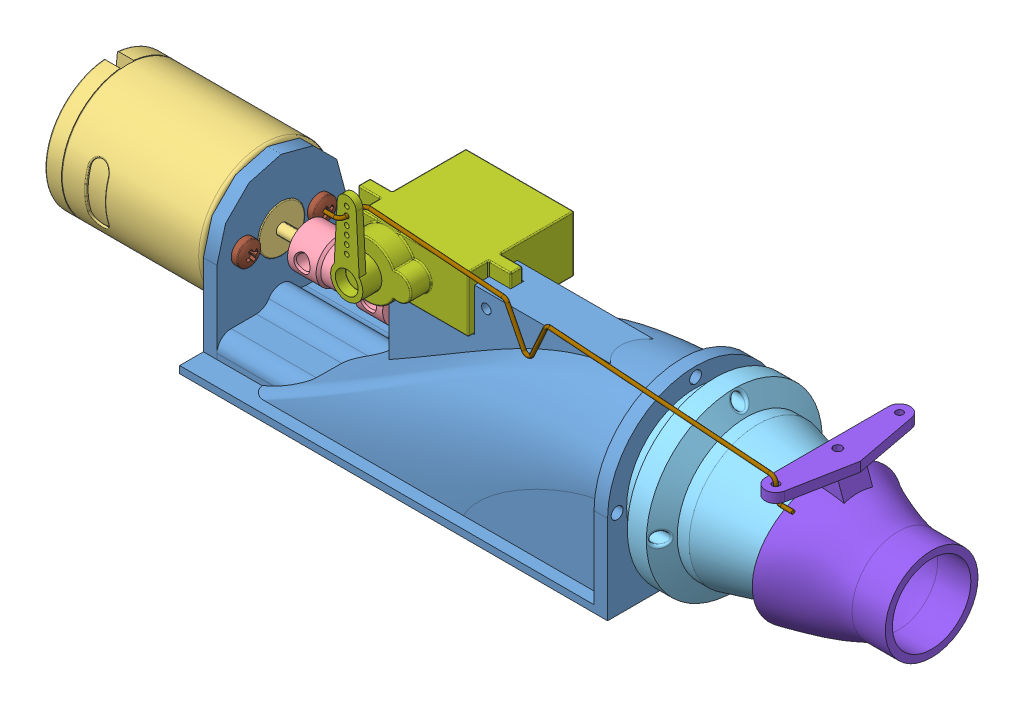
SolidWorks assembly assembly 25mm impeller jet drive, configuration Default. Lengths in mm.
Overall size (175.66 47.97 37.3).
16 component instances, 13 part files, 33 mates.
Components (placement in the parent):
- jet drive for 25mm impeller-1: jet drive for 25mm impeller [Default] at (-2.105 -21.3255 0) size (90 39.15 37)
- shaft-1: shaft [Default] at (-69.955 -0.679 0) x (1 0 0) z (0 -0.374675 0.927156) size (85 3 3)
- RS365 DC Motor-1: RS365 DC Motor [Default] at (-77.105 -0.679 0) x (1 0 0) z (0 1 0) size (51 27.5 27.5)
- shaft coupler-1: shaft coupler [Default] at (-63.411 -0.679 0) x (-1 0 0) z (0 -0.042922 -0.999078) size (20 9 9)
- stator-1: stator [Default] at (-4.955 -0.679 0) size (35.93 37.32 37.3)
- impeller 25min OD-1: impeller 25min OD [Default] at (11.045 -0.679 0) x (0 0.907746 0.419521) z (0 -0.419521 0.907746) size (24.22 20 24.19)
- servo towerpro sg90-1: servo towerpro sg90 [Default] at (-55.63 10.746 -16.6125) x (1 0 0) z (0 -1 0) size (32.05 31 21.88)
- nozzle-1: nozzle [Default] at (25.545 -0.679 0) x (0 0 -1) z (0 -1 0) size (31.46 22.02 31.51)
- wire-1: wire [Default] at origin size (95.63 10.1 6.02)
- bearing-1: bearing [Default] at (-48.4939 -0.679 0) x (0 -0.407486 -0.913211) z (-1 0 0) size (4 4 4)
- bearing-2: bearing [Default] at (-58.105 -0.679 0) x (0 0.170235 0.985404) z (-1 0 0) size (4 4 4)
- bearing-3: bearing [Default] at (15.045 -0.679 0) x (0 0.944365 0.328901) z (-1 0 0) size (4 4 4)
- hull-1: hull [Default] at origin size (333.75 30.44 61.92) (hidden)
- pan head cross recess screw_iso-1: pan head cross recess screw_iso [ISO 7045 - M2.5 x 5 - Z - 5N] at (-87.155 -0.679 8) x (-1 0 0) z (0 -0.924225 -0.381849) size (7.05 5 5)
- pan head cross recess screw_iso-2: pan head cross recess screw_iso [ISO 7045 - M2.5 x 5 - Z - 5N] at (-87.155 -0.679 -8) x (-1 0 0) z (0 -0.85199 -0.523557) size (7.05 5 5)
- countersunk flat head cross recess screw_iso-2: countersunk flat head cross recess screw_iso [ISO 7046-1 - M2.5 x 5 - Z - 5N] at (-92.105 -13.679 0) size (5 4.7 4.7)
Mates (geometry in assembly coordinates):
- Coincident1: coincident aligned: line of jet drive for 25mm impeller-1 through (2.85 -89.255 -0.679) axis (0 -1 0); line of 2.3mm shaft-1 through (85 15.045 -0.679) axis (0 -1 0)
- Coincident5: coincident anti-aligned: line of 2.3mm shaft-1 through (85 15.045 -0.679) axis (0 -1 0); line of shaft coupler 2.3mm aliexpress-1 through (7 -76.911 -0.679) axis (0 1 0)
- Coincident6: coincident anti-aligned: line of 2.3mm shaft-1 through (85 15.045 -0.679) axis (0 -1 0); line of stator-1 through (16.5 11.045 -0.679) axis (0 1 0)
- Coincident7: coincident anti-aligned: plane of jet drive for 25mm impeller-1 through (-4.955 -0.679 0) normal (1 0 0); plane of stator-1 through (-4.955 -0.679 -14.5) normal (-1 0 0)
- Coincident8: coincident anti-aligned: line of 2.3mm shaft-1 through (85 15.045 -0.679) axis (0 -1 0); line of impeller 25min OD-1 through (13 -1.955 -0.679) axis (0 1 0)
- Coincident9: coincident anti-aligned: plane of jet drive for 25mm impeller-1 through (-2.104 4.821 -4.5) normal (0 1 0); plane of servo towerpro sg90-1 through (-55.63 4.821 -16.6125) normal (0 -1 0)
- Coincident10: coincident aligned: line of 2.3mm shaft-1 through (85 15.045 -0.679) axis (0 -1 0); line of nozzle-1 through (7 47.545 -0.679) axis (0 -1 0)
- Parallel1: parallel aligned: plane of nozzle-1 through (27.795 17.821 13) normal (0 1 0)
- Coincident11: coincident anti-aligned: line of stator-1 through (2.2903 27.795 -11.679) axis (0 0 1); line of nozzle-1 through (27.795 17.821 0) axis (0 -1 0)
- Coincident12: coincident anti-aligned: line of 2.3mm shaft-1 through (85 15.045 -0.679) axis (0 -1 0); line of bearing-1 through (4 -52.4939 -0.679) axis (0 1 0)
- Coincident13: coincident anti-aligned: line of 2.3mm shaft-1 through (85 15.045 -0.679) axis (0 -1 0); line of bearing-2 through (4 -62.105 -0.679) axis (0 1 0)
- Coincident14: coincident anti-aligned: line of 2.3mm shaft-1 through (85 15.045 -0.679) axis (0 -1 0); line of bearing-3 through (4 11.045 -0.679) axis (0 1 0)
- Coincident15: coincident anti-aligned: plane of stator-1 through (11.045 -0.679 0) normal (-1 0 0); plane of impeller 25min OD-1 through (11.045 3.8598 2.0976) normal (1 0 0)
- Coincident16: coincident anti-aligned: plane of jet drive for 25mm impeller-1 through (-58.105 -2.679 0) normal (-1 0 0); plane of bearing-2 through (-58.105 -0.679 0) normal (1 0 0)
- Coincident17: coincident anti-aligned: plane of jet drive for 25mm impeller-1 through (-52.4939 -2.179 0) normal (1 0 0); plane of bearing-1 through (-52.4939 -0.679 0) normal (-1 0 0)
- Coincident18: coincident anti-aligned: plane of bearing-3 through (11.045 -0.679 0) normal (-1 0 0); plane of impeller 25min OD-1 through (11.045 3.8598 2.0976) normal (1 0 0)
- Coincident22: coincident anti-aligned: line of jet drive for 25mm impeller-1 through (-89.255 -0.679 8) axis (-1 0 0); line of RS365 DC Motor-1 through (-96.855 -0.679 8) axis (1 0 0)
- Coincident23: coincident anti-aligned: line of jet drive for 25mm impeller-1 through (-89.255 -0.679 -8) axis (-1 0 0); line of RS365 DC Motor-1 through (-96.855 -0.679 -8) axis (1 0 0)
- Coincident24: coincident anti-aligned: plane of jet drive for 25mm impeller-1 through (-92.105 -21.3255 18.5) normal (-1 0 0); plane of RS365 DC Motor-1 through (-92.105 -0.679 -4.95) normal (1 0 0)
- Coincident26: coincident anti-aligned: plane of jet drive for 25mm impeller-1 through (-39.605 -21.3255 0) normal (-1 0 0); plane of servo towerpro sg90-1 through (-39.605 4.821 -1.1125) normal (1 0 0)
- Coincident32: coincident anti-aligned: plane of jet drive for 25mm impeller-1 through (-44.105 13.821 1.3875) normal (0 0 -1); plane of servo towerpro sg90-1 through (-39.605 4.821 1.3875) normal (0 0 1)
- Coincident33: coincident: plane of jet drive for 25mm impeller-1 through (-2.105 -21.3255 0) normal (0 0 1)
- Coincident34: coincident aligned: plane of 2.3mm shaft-1 through (15.045 -0.679 0) normal (1 0 0); plane of bearing-3 through (15.045 -0.679 0) normal (1 0 0)
- Coincident35: coincident anti-aligned: line of jet drive for 25mm impeller-1 through (1 -55.2994 3.821) axis (0 0 1); line of screw servo-1 through (7 -55.2994 3.321) axis (0 0 -1)
- Coincident36: coincident anti-aligned: plane of jet drive for 25mm impeller-1 through (-55.2994 3.821 0) normal (0 1 0); plane of screw servo-1 through (-54.2994 3.321 0) normal (0 -1 0)
- Coincident37: coincident aligned: line of jet drive for 25mm impeller-1 through (-41.605 10.746 1.3875) axis (0 0 1); line of screw servo-2 through (-41.605 10.746 4.5) axis (0 0 -1)
- Coincident38: coincident anti-aligned: plane of jet drive for 25mm impeller-1 through (-2.104 4.821 4.5) normal (0 0 1); circle of screw servo-2
- Coincident39: coincident anti-aligned: line of jet drive for 25mm impeller-1 through (-89.255 -0.679 8) axis (-1 0 0); line of pan head cross recess screw_iso-1 through (-92.5233 -0.679 8) axis (1 0 0)
- Coincident40: coincident anti-aligned: plane of jet drive for 25mm impeller-1 through (-89.255 -0.679 0) normal (1 0 0); plane of pan head cross recess screw_iso-1 through (-89.255 -0.2016 6.8447) normal (-1 0 0)
- Coincident41: coincident anti-aligned: line of jet drive for 25mm impeller-1 through (-89.255 -0.679 -8) axis (-1 0 0); line of pan head cross recess screw_iso-2 through (-92.5233 -0.679 -8) axis (1 0 0)
- Coincident42: coincident anti-aligned: plane of jet drive for 25mm impeller-1 through (-89.255 -0.679 0) normal (1 0 0); plane of pan head cross recess screw_iso-2 through (-89.255 -0.0245 -9.065) normal (-1 0 0)
- Coincident43: coincident aligned: line of jet drive for 25mm impeller-1 through (4.2788 -84.9763 -13.679) axis (0 -1 0); line of countersunk flat head cross recess screw_iso-2 through (3.2515 -87.105 -13.679) axis (0 -1 0)
- Coincident44: coincident aligned: plane of countersunk flat head cross recess screw_iso-2 through (-92.105 -13.679 0) normal (-1 0 0); plane of jet drive for 25mm impeller-1 through (-92.105 -0.679 0) normal (-1 0 0)
